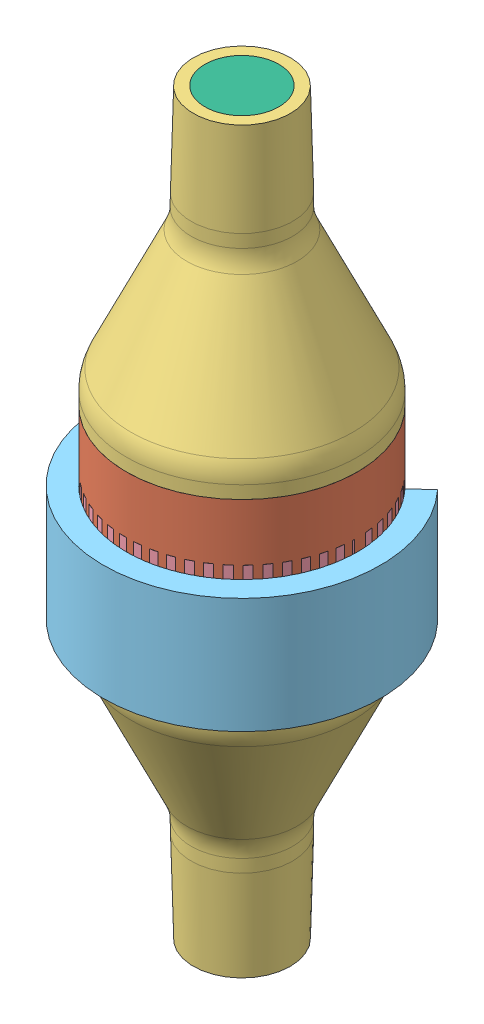
SolidWorks assembly Montagem_válvula_flow_simulation, configuration 0 %. Lengths in mm.
Overall size (77.27 160.31 66.9).
8 component instances, 7 part files, 19 mates.
Components (placement in the parent):
- Catraca-1: Catraca [Valor predeterminado] at (168.0147 154.5281 120.9146) x (-0.199699 0 0.979857) z (0 -1 0) size (35.88 67.5 10)
- Peça 3 - Fêmea-Macho-1: Peça 3 - Fêmea-Macho [Valor predeterminado] at (168.0147 174.5281 120.9146) x (0 0 1) z (1 0 0) size (50 35 50)
- Peça 1 - Funil-1: Peça 1 - Funil [Valor predeterminado] at (168.0147 129.5281 120.9146) x (-0.434479 0 -0.900682) z (0 1 0) size (50 50 60.16)
- Peça 1 - Funil-2: Peça 1 - Funil [Valor predeterminado] at (168.0147 179.5281 120.9146) x (0.897976 0 0.440044) z (0 -1 0) size (50 50 60.16)
- Luva-1: Luva [Valor predeterminado] at (168.0147 142.1894 120.9146) x (0.978008 0 -0.208569) z (0.208569 0 0.978008) size (50 20 50)
- Peça 2 - Escape-3: Peça 2 - Escape [Valor predeterminado] at (168.0147 134.5281 120.9146) size (59.99 25 55)
- LID5-1: LID5 [Valor predeterminado] at origin size (16.46 0.93 16.46)
- LID6-1: LID6 [Valor predeterminado] at origin size (16.46 0.93 16.46)
Mates (geometry in assembly coordinates):
- Coincident24: coincident: circle of assembly; circle of assembly; circle of Peça 3 - Fêmea-Macho-1; circle of Peça 1 - Funil-2
- Coincident32: coincident: circle of assembly; circle of assembly; circle of Peça 1 - Funil-1; circle of Peça 2 - Escape-3
- Concentric1: concentric: cylinder of assembly; circle of assembly; cylinder of Peça 3 - Fêmea-Macho-1 through (168.0147 139.5281 120.9146) axis (0 1 0) radius 1; circle of Peça 2 - Escape-3
- Concentric2: concentric: cylinder of assembly; circle of assembly; cylinder of Peça 3 - Fêmea-Macho-1 through (168.0147 139.5281 131.4146) axis (0 1 0) radius 1; circle of Peça 2 - Escape-3
- Coincident36: coincident: circle of assembly; circle of assembly; circle of Catraca-1; circle of Peça 2 - Escape-3
- Coincident37: coincident: plane of assembly; plane of assembly; plane of Peça 3 - Fêmea-Macho-1 through (168.0147 144.5281 120.9146) normal (0 -1 0); plane of Peça 2 - Escape-3 through (168.0147 144.5281 120.9146) normal (0 1 0)
- LimitAngle1: limit planar angle = 2.068425 rad: plane of assembly; plane of assembly; plane of Catraca-1 through (168.0147 144.5281 120.9146) normal (0.319693 0 -0.947521); plane of Peça 2 - Escape-3 through (168.0147 56.1784 120.9146) normal (-0.68 0 -0.733212)
- Concentric4: concentric: circle of assembly; circle of assembly; circle of Peça 3 - Fêmea-Macho-1; circle of Luva-1
- Coincident39: coincident: line of assembly; point of assembly; line of Catraca-1 through (148.4176 144.5281 116.9206) axis (-0.979857 0 -0.199699); point of Peça 2 - Escape-3
- Coincident40: coincident: line of ? through (177.052 144.5281 103.0729) axis (0.451864 0 -0.892087); unknown of Peça 2 - Escape-3
- Coincident45: coincident: line of ? through (148.019 144.5281 121.3301) axis (-0.999784 0 0.020773); unknown of Peça 2 - Escape-3
- Coincident46: coincident: line of ? through (172.7499 144.5281 101.4832) axis (0.236759 0 -0.971568); unknown of Peça 2 - Escape-3
- Coincident47: coincident: line of ? through (168.1988 144.5281 100.9155) axis (0.009204 0 -0.999958); unknown of Peça 2 - Escape-3
- Coincident48: coincident: line of ? through (163.638 144.5281 101.3994) axis (-0.218836 0 -0.975762); unknown of Peça 2 - Escape-3
- Coincident49: coincident: line of ? through (159.3074 144.5281 102.9095) axis (-0.435367 0 -0.900253); unknown of Peça 2 - Escape-3
- Coincident50: coincident: line of ? through (155.4346 144.5281 105.3666) axis (-0.629004 0 -0.777402); unknown of Peça 2 - Escape-3
- Coincident51: coincident: line of ? through (152.2235 144.5281 108.6412) axis (-0.789563 0 -0.61367); unknown of Peça 2 - Escape-3
- Coincident52: coincident: line of ? through (149.8427 144.5281 112.5613) axis (-0.9086 0 -0.417666); unknown of Peça 2 - Escape-3
- Coincident53: coincident: line of assembly; point of assembly; line of Catraca-1 through (148.4176 144.5281 116.9206) axis (-0.979857 0 -0.199699); point of Peça 2 - Escape-3
